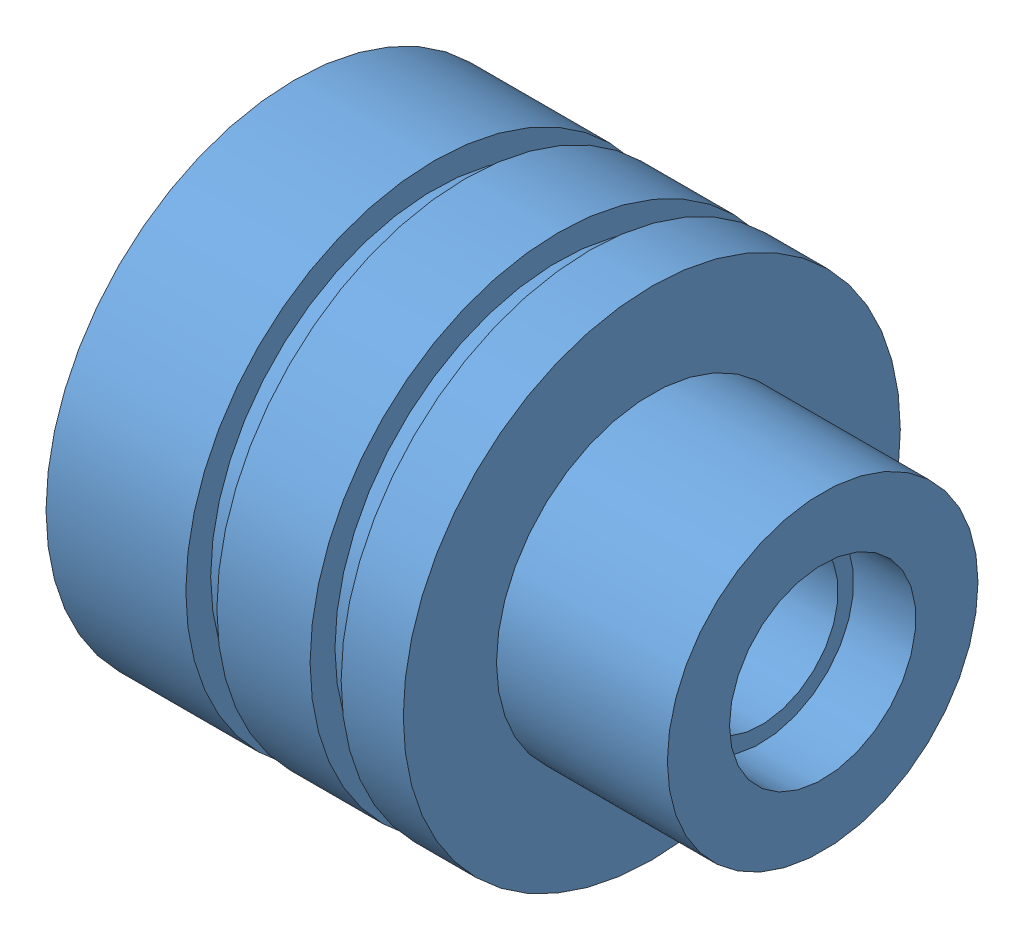
SolidWorks assembly Detector, configuration Standard. Lengths in mm.
Overall size (17 16 16).
2 component instances, 2 part files, 2 mates.
Components (placement in the parent):
- Detector_Zapfen-1: Detector_Zapfen [Standard] at (-5.8545 1.0976 17) size (17 16 16)
- Detector_rückenteil-1: Detector_rückenteil [Standard] at (-0.2545 1.0976 17) x (0 0.350017 -0.936743) z (1 0 0) size (10 8 5.6)
Mates (geometry in assembly coordinates):
- Konzentrisch1: concentric anti-aligned: cylinder of Detector_Zapfen-1 through (-5.8545 1.0976 17) axis (-1 0 0) radius 5; cylinder of Detector_rückenteil-1 through (-5.8545 1.0976 17) axis (1 0 0) radius 5
- Deckungsgleich1: coincident anti-aligned: plane of Detector_Zapfen-1 through (-0.2545 6.0976 17) normal (-1 0 0); plane of Detector_rückenteil-1 through (-0.2545 1.0976 17) normal (1 0 0)
